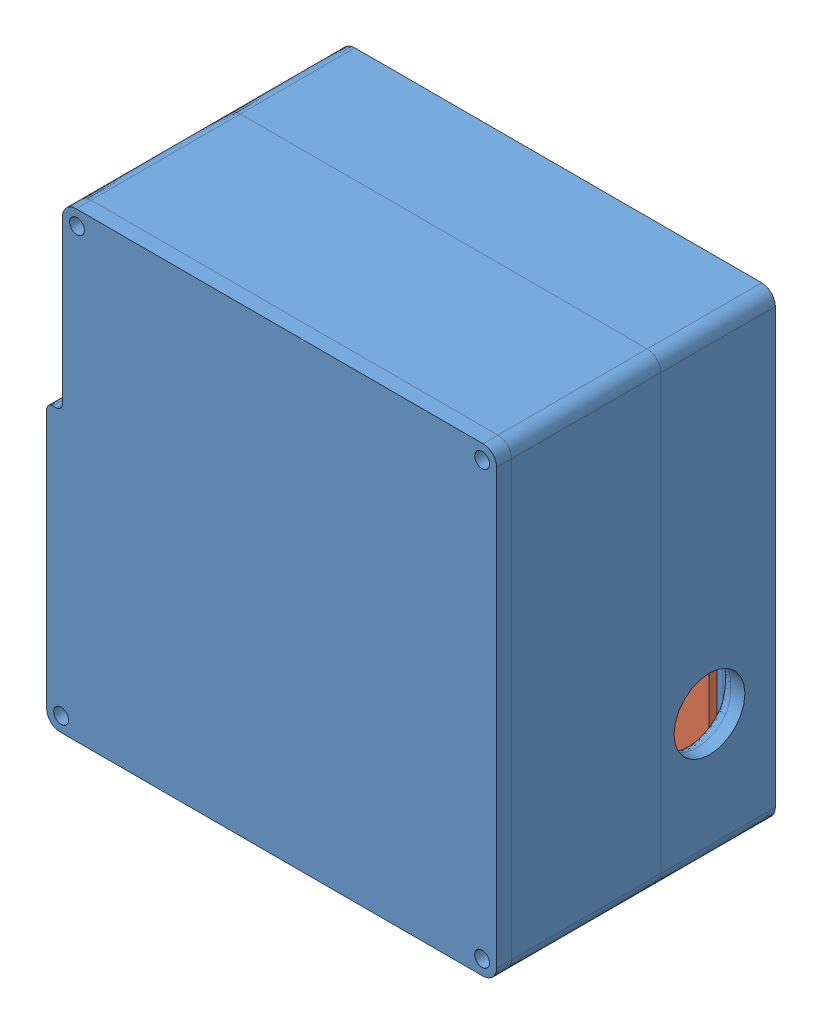
SolidWorks assembly Assem1, configuration Default. Lengths in mm.
Overall size (90.43 92.65 56).
4 component instances, 2 part files, 10 mates.
Components (placement in the parent):
- PCB_Pad-1: PCB_Pad [Default] at (-50.9538 -43.0746 1.4111) size (90.43 92.65 23)
- PCB-1: PCB [Default] at (-50.9538 -43.0746 4.1611) size (74.93 80.64 1.6)
- PCB_Pad-2: PCB_Pad [spacer] at (-50.9538 -43.0746 21.4111) size (90.43 92.65 30)
- PCB_Pad-3: PCB_Pad [lid] at (-50.9538 -43.0746 51.4111) size (90.43 92.65 3)
Mates (geometry in assembly coordinates):
- Concentric1: concentric aligned: cylinder of PCB_Pad-1 through (-46.9698 -39.0486 4.1611) axis (0 0 -1) radius 1.5; cylinder of PCB-1 through (-46.9698 -39.0486 5.7613) axis (0 0 -1) radius 1.5
- Concentric2: concentric aligned: cylinder of PCB_Pad-1 through (20.0302 -39.0486 4.1611) axis (0 0 -1) radius 1.5; cylinder of PCB-1 through (20.0302 -39.0486 5.7613) axis (0 0 -1) radius 1.5
- Concentric3: concentric aligned: cylinder of PCB_Pad-1 through (-17.5943 32.9514 4.1611) axis (0 0 -1) radius 1.5; cylinder of PCB-1 through (-17.5943 32.9514 5.7613) axis (0 0 -1) radius 1.5
- Coincident1: coincident anti-aligned: plane of PCB_Pad-1 through (-50.9538 -43.0746 4.1611) normal (0 0 1); plane of PCB-1 through (-50.9538 -43.0746 4.1611) normal (0 0 -1)
- Concentric4: concentric anti-aligned: cylinder of PCB_Pad-1 through (27.0473 -46.1457 -1.5889) axis (0 0 1) radius 1.5; cylinder of PCB_Pad-2 through (27.0473 -46.1457 51.4111) axis (0 0 -1) radius 1.5
- Concentric5: concentric anti-aligned: cylinder of PCB_Pad-1 through (-57.5249 -46.1457 -1.5889) axis (0 0 1) radius 1.5; cylinder of PCB_Pad-2 through (-57.5249 -46.1457 51.4111) axis (0 0 -1) radius 1.5
- Coincident2: coincident anti-aligned: plane of PCB_Pad-1 through (-50.9538 -43.0746 21.4111) normal (0 0 1); plane of PCB_Pad-2 through (-50.9538 -43.0746 21.4111) normal (0 0 -1)
- Concentric6: concentric: cylinder of PCB_Pad-2 through (27.0473 -46.1457 51.4111) axis (0 0 -1) radius 1.5; cylinder of PCB_Pad-3 through (27.0473 -46.1457 78.8877) axis (0 0 -1) radius 1.5
- Concentric7: concentric: cylinder of PCB_Pad-2 through (-57.5249 -46.1457 51.4111) axis (0 0 -1) radius 1.5; cylinder of PCB_Pad-3 through (-57.5249 -46.1457 54.4111) axis (0 0 -1) radius 1.5
- Coincident3: coincident anti-aligned: plane of PCB_Pad-2 through (-50.9538 -43.0746 51.4111) normal (0 0 1); plane of PCB_Pad-3 through (-50.9538 -43.0746 51.4111) normal (0 0 -1)
